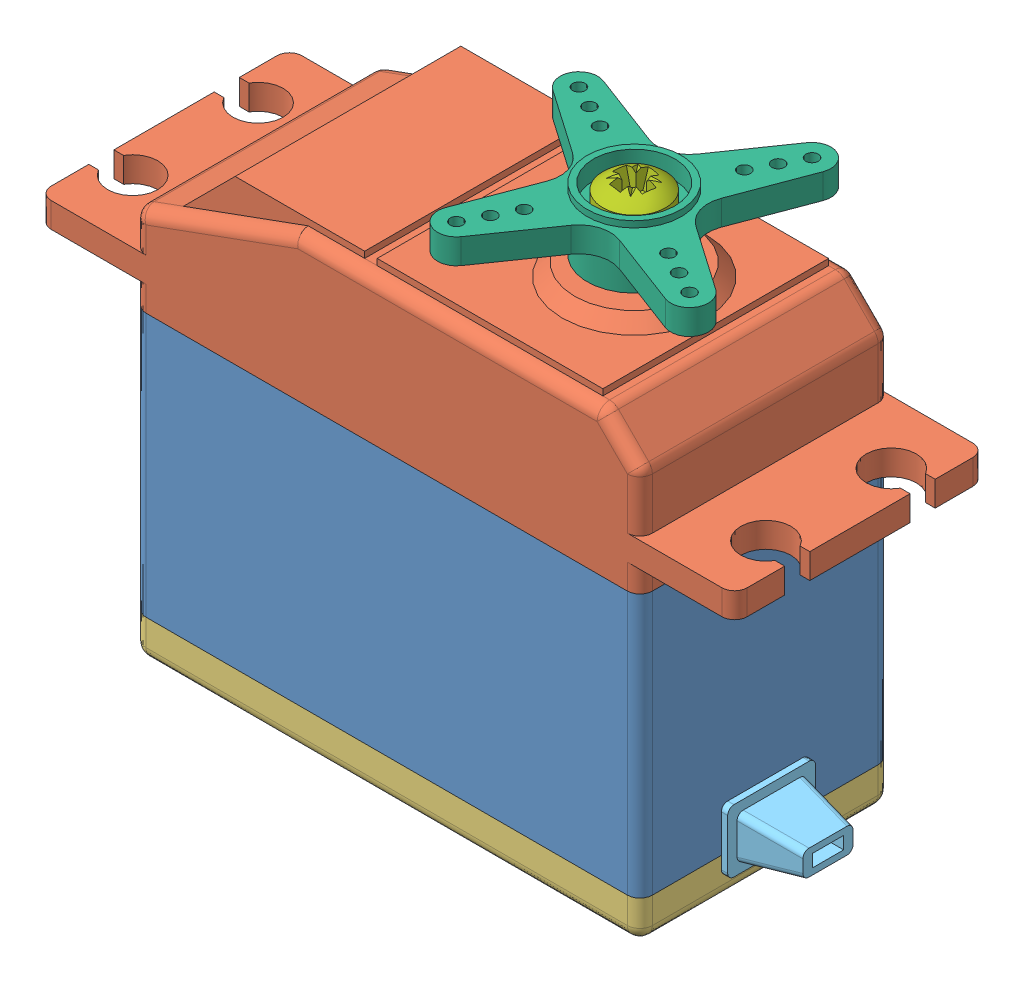
SolidWorks assembly Servomoteur Futuba S3003, configuration Défaut. Lengths in mm.
Overall size (55.5 42.98 32.41).
7 component instances, 7 part files, 15 mates.
Components (placement in the parent):
- Boitier-1: Boitier [Défaut] at (8.3252 -16.2642 40.4) size (40.4 21 20)
- Couvercle supérieure-1: Couvercle supérieure [Défaut] at (9.3643 6.7358 40.4) size (55.5 13 20)
- Couvercle inférieure-1: Couvercle inférieure [Défaut] at (4.9957 -19.3642 40.4) size (40.4 3.1 20)
- Axe-1: Axe [Défaut] at (9.3643 15.2358 40.4) size (5 16 5)
- Passe fil-1: Passe fil [Défaut] at (17.8143 -15.2642 40.4) x (0 0 -1) z (1 0 0) size (7 5 7.5)
- Palonnier-1: Palonnier [Défaut] at (9.3643 21.7358 40.4) x (0.465117 0 -0.885249) z (0 1 0) size (24 24 5)
- Vis CBL Z, M 2.5 - 5-1: Vis CBL Z, M 2.5 - 5 [Défaut] at (9.3643 21.7358 40.4) x (0.991239 0 0.132079) z (0 1 0) size (5 5 6.88)
Mates (geometry in assembly coordinates):
- Coïncidente1: coincident aligned: plane of Boitier-1 through (-20.5857 4.7358 50.4) normal (0 0 1); plane of Couvercle supérieure-1 through (-28.1357 8.7358 50.4) normal (0 0 1)
- Coïncidente2: coincident aligned: plane of Boitier-1 through (-20.5857 4.7358 30.4) normal (-1 0 0); plane of Couvercle supérieure-1 through (-20.5857 4.7358 30.4) normal (-1 0 0)
- Coïncidente3: coincident anti-aligned: plane of Boitier-1 through (8.3252 4.7358 40.4) normal (0 1 0); plane of Couvercle supérieure-1 through (9.3643 4.7358 40.4) normal (0 -1 0)
- Coïncidente4: coincident aligned: plane of Boitier-1 through (-20.5857 4.7358 50.4) normal (0 0 1); plane of Couvercle inférieure-1 through (-20.5857 -18.3642 50.4) normal (0 0 1)
- Coïncidente5: coincident aligned: plane of Boitier-1 through (-20.5857 4.7358 30.4) normal (-1 0 0); plane of Couvercle inférieure-1 through (-20.5857 -18.3642 30.4) normal (-1 0 0)
- Coïncidente6: coincident anti-aligned: plane of Boitier-1 through (8.3252 -16.2642 40.4) normal (0 -1 0); plane of Couvercle inférieure-1 through (4.9957 -16.2642 40.4) normal (0 1 0)
- Coaxiale1: concentric aligned: cylinder of Couvercle supérieure-1 through (9.3643 4.7358 40.4) axis (0 1 0) radius 2.65; cylinder of Axe-1 through (9.3643 5.2358 40.4) axis (0 1 0) radius 2.5
- Distance1: distance = 3.5 mm aligned: plane of Axe-1 through (9.3643 21.2358 40.4) normal (0 1 0); plane of Couvercle supérieure-1 through (4.6143 17.7358 40.4) normal (0 1 0)
- Coïncidente7: coincident anti-aligned: plane of Boitier-1 through (8.3252 -16.2642 40.4) normal (0 0 1); plane of Passe fil-1 through (17.8143 -15.2642 40.4) normal (0 0 -1)
- Coïncidente8: coincident anti-aligned: plane of Boitier-1 through (19.8143 4.7358 30.4) normal (1 0 0); plane of Passe fil-1 through (19.8143 -17.2642 43.4) normal (-1 0 0)
- Coïncidente9: coincident: line of Boitier-1 through (19.8143 -16.2642 49.4) axis (0 0 -1); plane of Passe fil-1 through (19.8143 -16.2642 42.4) normal (0 -1 0)
- Coaxiale2: concentric aligned: cylinder of Axe-1 through (9.3643 5.2358 40.4) axis (0 1 0) radius 2.5; cylinder of Palonnier-1 through (9.3643 18.2358 40.4) axis (0 1 0) radius 3.75
- Coïncidente10: coincident anti-aligned: plane of Axe-1 through (9.3643 21.2358 40.4) normal (0 1 0); plane of Palonnier-1 through (9.3643 21.2358 40.4) normal (0 -1 0)
- Coaxiale3: concentric aligned: cylinder of Palonnier-1 through (9.3643 21.7358 40.4) axis (0 1 0) radius 3.25; cylinder of Vis CBL Z, M 2.5 - 5-1 through (9.3643 16.7358 40.4) axis (0 1 0) radius 1.25
- Coïncidente11: coincident anti-aligned: plane of Palonnier-1 through (9.3643 21.7358 40.4) normal (0 1 0); plane of Vis CBL Z, M 2.5 - 5-1 through (9.3643 21.7358 40.4) normal (0 -1 0)
